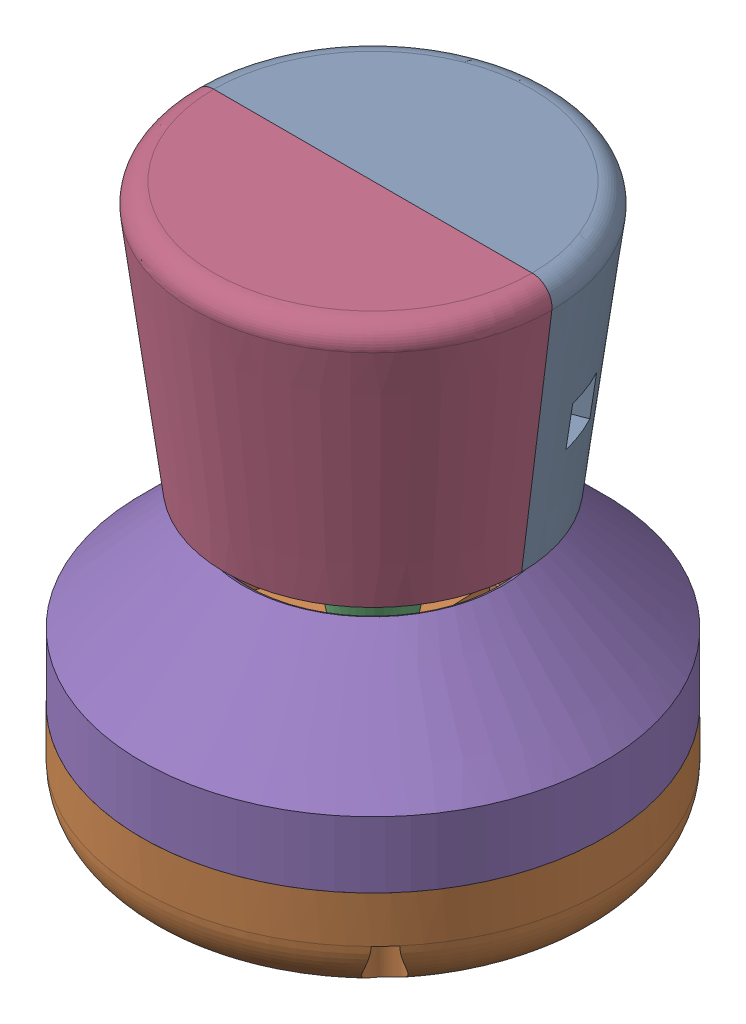
SolidWorks assembly SM_assem, configuration Default. Lengths in mm.
Overall size (98.92 83.6 98.92).
5 component instances, 5 part files, 9 mates.
Components (placement in the parent):
- SM_joystick_topper_front-1: SM_joystick_topper_front [Default] at (0.8466 -9.7971 6.2092) size (54.2 40 27.13)
- SM_bottom-1: SM_bottom [Default] at (0.8466 -53.4001 6.2092) x (-0.037994 0 -0.999278) z (0.999278 0 -0.037994) size (70 15 70)
- SM_joystick-1: SM_joystick [Default] at (0.8466 -31.52 6.2092) x (0.975149 0 -0.221552) z (0.221552 0 0.975149) size (26 50 24.38)
- SM_joystick_topper_back-1: SM_joystick_topper_back [Default] at (0.8466 -9.7971 6.2092) x (-1 0 0) z (0 0 -1) size (54.2 40 27.13)
- SM_rim-1: SM_rim [Default] at (0.8466 -38.4001 6.2092) x (-0.733462 0 -0.67973) z (0.67973 0 -0.733462) size (70 25.36 70)
Mates (geometry in assembly coordinates):
- Concentric1: concentric aligned: cylinder of SM_bottom-1 through (25.0509 -38.4001 28.6403) axis (0 -1 0) radius 1.15; cylinder of SM_rim-1 through (25.0509 -28.4001 28.6403) axis (0 -1 0) radius 1.15
- Concentric2: concentric aligned: cylinder of SM_bottom-1 through (23.2777 -38.4001 -17.995) axis (0 -1 0) radius 1.15; cylinder of SM_rim-1 through (23.2777 -28.4001 -17.995) axis (0 -1 0) radius 1.15
- Coincident1: coincident anti-aligned: plane of SM_bottom-1 through (0.8466 -38.4001 6.2092) normal (0 1 0); plane of SM_rim-1 through (26.5178 -38.4001 29.9998) normal (0 -1 0)
- Concentric3: concentric anti-aligned: cylinder of SM_joystick-1 through (0.8466 9.48 6.2092) axis (0 1 0) radius 8; circle of SM_rim-1
- Concentric4: concentric aligned: cylinder of SM_joystick_topper_front-1 through (0.8466 30.2029 6.2092) axis (0 1 0) radius 3; cylinder of SM_joystick-1 through (0.8466 9.48 6.2092) axis (0 1 0) radius 8
- Coincident2: coincident anti-aligned: plane of SM_joystick_topper_front-1 through (3.8466 18.48 6.2092) normal (0 -1 0); plane of SM_joystick-1 through (0.8466 18.48 6.2092) normal (0 1 0)
- Coincident3: coincident anti-aligned: plane of SM_joystick_topper_front-1 through (0.8466 -9.7971 6.2092) normal (0 0 1); plane of SM_joystick_topper_back-1 through (0.8466 -9.7971 6.2092) normal (0 0 -1)
- Concentric5: concentric anti-aligned: cylinder of SM_joystick_topper_front-1 through (25.1563 20.8054 1.2092) axis (0 0 1) radius 1.15; cylinder of SM_joystick_topper_back-1 through (25.1563 20.8054 11.2092) axis (0 0 -1) radius 1.15
- Concentric6: concentric anti-aligned: cylinder of SM_joystick_topper_front-1 through (-20.1872 -5.4019 1.2092) axis (0 0 1) radius 1.15; cylinder of SM_joystick_topper_back-1 through (-20.1872 -5.4019 11.2092) axis (0 0 -1) radius 1.15
